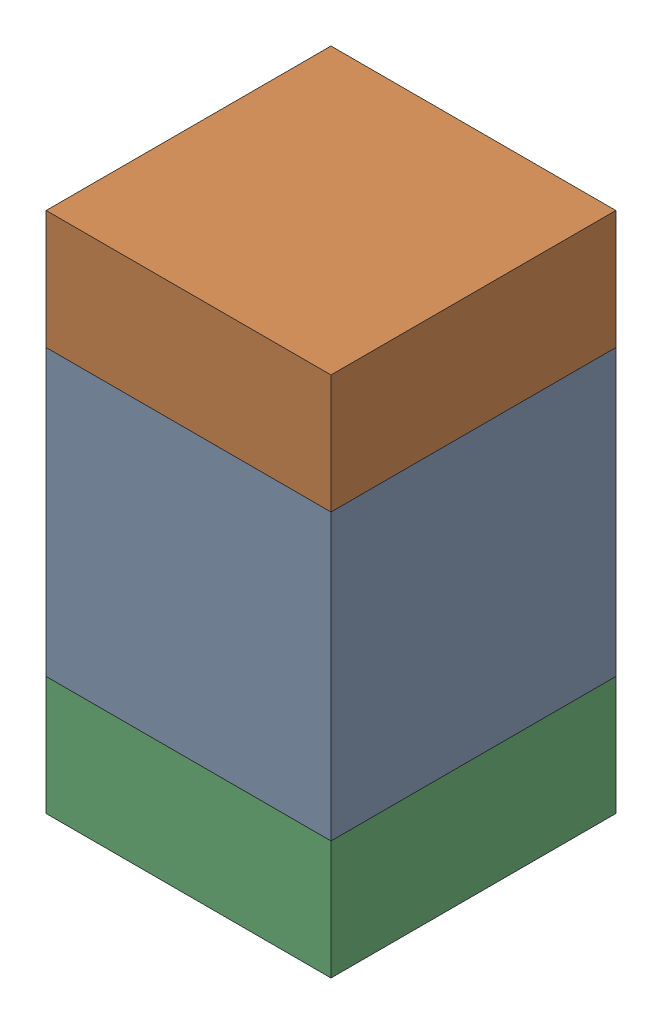
SolidWorks assembly C423PCB, configuration Default. Lengths in mm.
Overall size (0.6 1.1 0.6).
6 component instances, 2 part files, 0 mates.
Components (placement in the parent):
- 761606048-1: 761606048 [Default] at (119.2 87.5 -2.2638) size (0.6 0.6 0.6)
  - Extruded_9-1: Extruded_9 [Default] at origin size (0.6 0.6 0.6)
- 854785296-1: 854785296 [Default] at (119.2 87.925 -2.2638) size (0.6 0.25 0.6)
  - Extruded_10-1: Extruded_10 [Default] at origin size (0.6 0.25 0.6)
- 854785296-2: 854785296 [Default] at (119.2 87.075 -2.2638) size (0.6 0.25 0.6)
  - Extruded_10-1: Extruded_10 [Default] at origin size (0.6 0.25 0.6)
